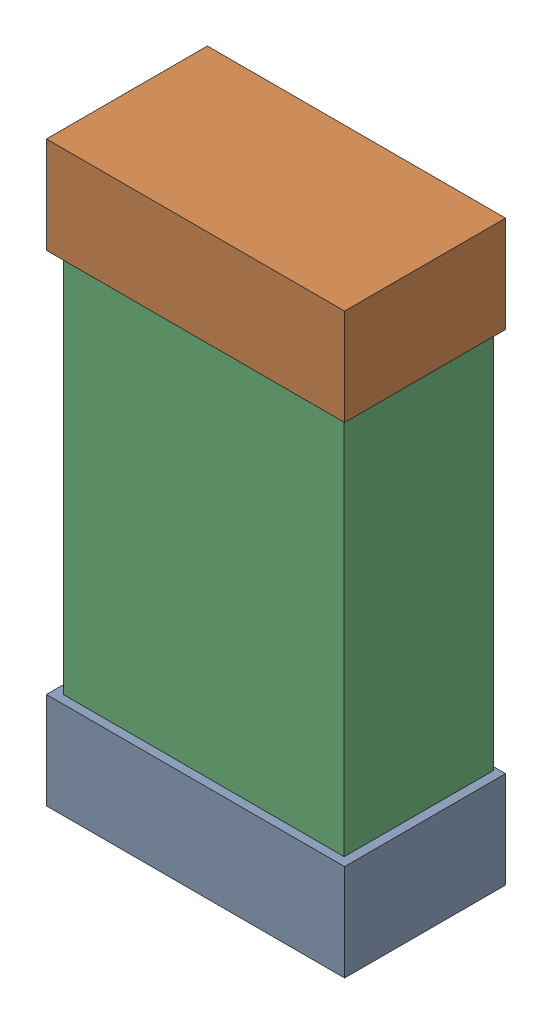
SolidWorks assembly C44, configuration Default. Lengths in mm.
Overall size (0.85 1.65 0.46).
6 component instances, 2 part files, 0 mates.
Components (placement in the parent):
- 432138512_36-1: 432138512_36 [Default] at (39.911 40.3643 -0.8715) size (0.85 0.28 0.46)
  - Extruded-1: Extruded [Default] at origin size (0.85 0.28 0.46)
- 432138512_37-1: 432138512_37 [Default] at (39.911 41.7358 -0.8715) size (0.85 0.28 0.46)
  - Extruded-1: Extruded [Default] at origin size (0.85 0.28 0.46)
- 432124816_18-1: 432124816_18 [Default] at (39.911 41.05 -0.8615) size (0.8 1.5 0.42)
  - Extruded (1)-1: Extruded (1) [Default] at origin size (0.8 1.5 0.42)
